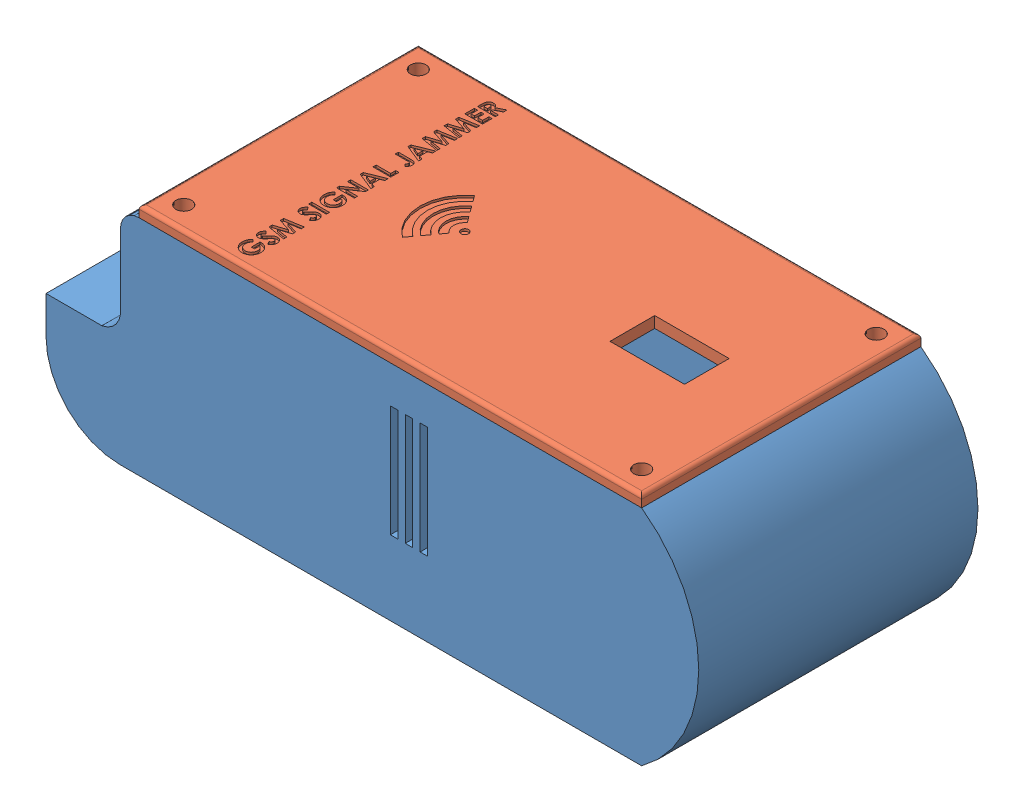
SolidWorks assembly Final Assembly, configuration Default. Lengths in mm.
Overall size (175.34 63 75).
2 component instances, 2 part files, 2 mates.
Components (placement in the parent):
- Base-1: Base [Default] at (-18.4628 77.3618 188.4793) size (175.34 60.51 75)
- Top Cover-1: Top Cover [Default] at (-13.4628 102.3618 225.9793) size (135 3 75)
Mates (geometry in assembly coordinates):
- Coincident1: coincident aligned: line of Base-1 through (-13.4628 102.3618 225.9793) axis (1 0 0); line of Top Cover-1 through (-13.4628 102.3618 225.9793) axis (1 0 0)
- Coincident2: coincident anti-aligned: line of Base-1 through (-13.4628 102.3618 222.9793) axis (0 0 -1); line of Top Cover-1 through (-13.4628 102.3618 150.9793) axis (0 0 1)
